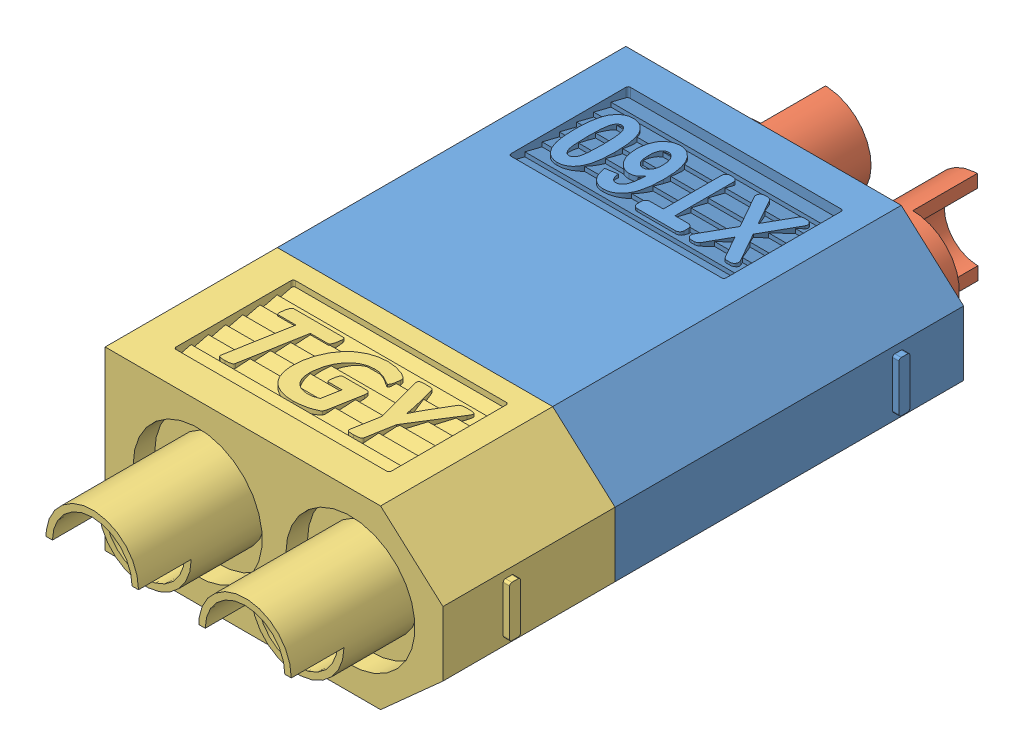
SolidWorks assembly XT-60_Macho, configuration Valor predeterminado. Lengths in mm.
Overall size (16.3 8.2 41.1).
4 component instances, 3 part files, 7 mates.
Components (placement in the parent):
- XT-60_Macho-1: XT-60_Macho [Valor predeterminado] at (-37.9952 28.536 -8.1) size (16.3 8.2 16.2)
- PinoXT-60_Macho-1: PinoXT-60_Macho [Valor predeterminado] at (-26.6452 32.636 -13.1) x (-0.008124 0.999967 0) z (0.999967 0.008124 0) size (4.3 26.83 4.3)
- PinoXT-60_Macho-2: PinoXT-60_Macho [Valor predeterminado] at (-33.7452 32.636 -13.1) x (-0.014321 -0.999897 0) z (-0.999897 0.014321 0) size (4.3 26.83 4.3)
- XT-60_Macho 1-1: XT-60_Macho 1 [Valor predeterminado] at (-37.9952 36.736 16.1) x (1 0 0) z (0 0 -1) size (16.3 8.2 21.5)
Mates (geometry in assembly coordinates):
- Concêntrico1: concentric aligned: cylinder of XT-60_Macho-1 through (-26.6452 32.636 8.1) axis (0 0 -1) radius 2.15; cylinder of PinoXT-60_Macho-1 through (-26.6452 32.636 -3.1) axis (0 0 -1) radius 2.15
- Concêntrico2: concentric aligned: cylinder of XT-60_Macho-1 through (-33.7452 32.636 8.1) axis (0 0 -1) radius 2.15; cylinder of PinoXT-60_Macho-2 through (-33.7452 32.636 -3.1) axis (0 0 -1) radius 2.15
- Distância1: distance = 1.4 mm aligned: plane of PinoXT-60_Macho-1 through (-26.6627 34.786 6.7) normal (0 0 1); plane of XT-60_Macho-1 through (-37.9952 28.536 8.1) normal (0 0 1)
- Distância2: distance = 1.4 mm aligned: plane of PinoXT-60_Macho-2 through (-33.776 30.4863 6.7) normal (0 0 1); plane of XT-60_Macho-1 through (-37.9952 28.536 8.1) normal (0 0 1)
- LimitDistance1: limit distance = 0 mm anti-aligned: plane of XT-60_Macho 1-1 through (-37.9952 38.536 8.1) normal (0 0 -1); plane of XT-60_Macho-1 through (-37.9952 28.536 8.1) normal (0 0 1)
- Width1: width aligned: plane of XT-60_Macho-1 through (-23.0452 31.4709 -1.3) normal (-1 0 0); plane of XT-60_Macho-1 through (-37.2452 35.986 -1.3) normal (1 0 0); plane of XT-60_Macho 1-1 through (-37.1952 29.336 0.4) normal (-1 0 0); plane of XT-60_Macho 1-1 through (-23.0952 33.7788 0.4) normal (1 0 0)
- Width2: width aligned: plane of XT-60_Macho 1-1 through (-37.1952 35.936 0.4) normal (0 1 0); plane of XT-60_Macho 1-1 through (-25.5014 29.336 0.4) normal (0 -1 0); plane of XT-60_Macho-1 through (-37.2452 29.286 -1.3) normal (0 1 0); plane of XT-60_Macho-1 through (-25.4822 35.986 -1.3) normal (0 -1 0)
